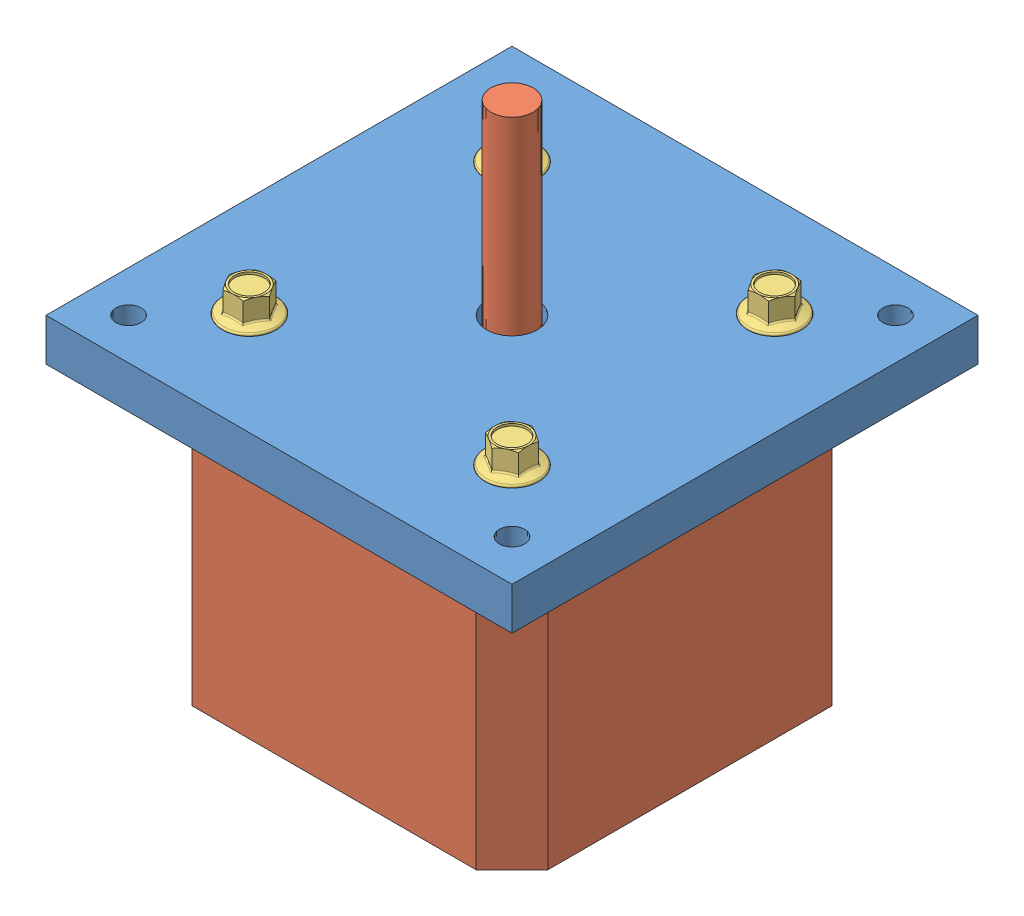
SolidWorks assembly Motor plus Mototr assembly, configuration Default. Lengths in mm.
Overall size (52 59.8 52).
6 component instances, 3 part files, 11 mates.
Components (placement in the parent):
- Motor and structure Mount-1: Motor and structure Mount [Default] at origin size (52 5 52)
- Stepper Motor-1: Stepper Motor [Default] at (0 -32.8 0) size (42 59.8 42)
- hex flange machine screw_am-1: hex flange machine screw_am [B18.6.7M - M3 x 0.5 x 4 Indented HFMS --4N] at (-15.5 8.2 -15.5) x (0 -1 0) z (-0.818372 0 0.574689) size (7.2 6.4 6.4)
- hex flange machine screw_am-5: hex flange machine screw_am [B18.6.7M - M3 x 0.5 x 4 Indented HFMS --4N] at (-15.5 8.2 15.5) x (0 -1 0) z (0.033508 0 0.999438) size (7.2 6.4 6.4)
- hex flange machine screw_am-7: hex flange machine screw_am [B18.6.7M - M3 x 0.5 x 4 Indented HFMS --4N] at (15.5 8.2 15.5) x (0 -1 0) z (-0.52414 0 0.851632) size (7.2 6.4 6.4)
- hex flange machine screw_am-9: hex flange machine screw_am [B18.6.7M - M3 x 0.5 x 4 Indented HFMS --4N] at (15.5 8.2 -15.5) x (0 -1 0) z (0.033508 0 0.999438) size (7.2 6.4 6.4)
Mates (geometry in assembly coordinates):
- Concentric4: concentric: circle of Motor and structure Mount-1; circle of Stepper Motor-1
- Parallel2: parallel: line of Motor and structure Mount-1 through (26 0 26) axis (-1 0 0); line of Stepper Motor-1 through (-16.76 0 21) axis (1 0 0)
- Coincident5: coincident: plane of Motor and structure Mount-1 through (0 0 0) normal (0 -1 0); plane of Stepper Motor-1 through (0 0 0) normal (0 1 0)
- Concentric8: concentric: circle of Motor and structure Mount-1; circle of hex flange machine screw_am-1
- Coincident20: coincident: plane of Motor and structure Mount-1 through (0 5 0) normal (0 1 0); plane of hex flange machine screw_am-1 through (-14.638 5 -14.2724) normal (0 -1 0)
- Concentric9: concentric: circle of Motor and structure Mount-1; circle of hex flange machine screw_am-5
- Coincident24: coincident: plane of Motor and structure Mount-1 through (0 5 0) normal (0 1 0); plane of hex flange machine screw_am-5 through (-14.0008 5 15.4497) normal (0 -1 0)
- Concentric10: concentric: circle of Motor and structure Mount-1; circle of hex flange machine screw_am-7
- Coincident25: coincident: plane of Motor and structure Mount-1 through (0 5 0) normal (0 1 0); plane of hex flange machine screw_am-7 through (16.7774 5 16.2862) normal (0 -1 0)
- Concentric11: concentric: circle of Motor and structure Mount-1; circle of hex flange machine screw_am-9
- Coincident26: coincident: plane of Motor and structure Mount-1 through (0 5 0) normal (0 1 0); plane of hex flange machine screw_am-9 through (16.9992 5 -15.5503) normal (0 -1 0)
